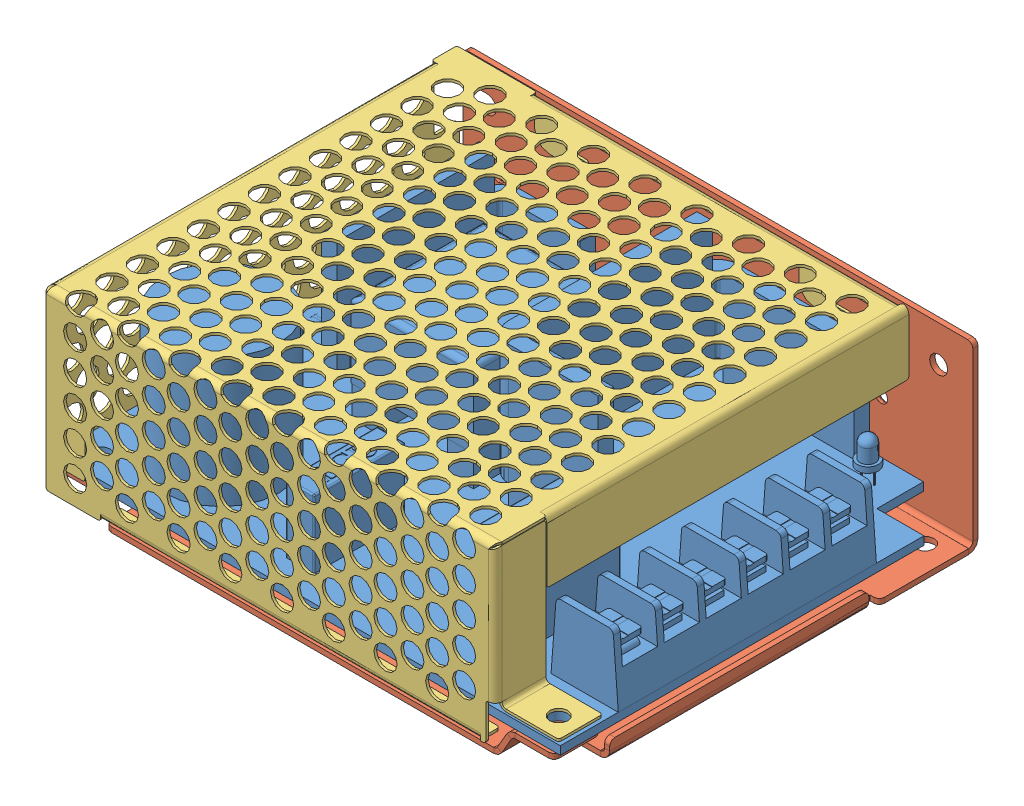
SolidWorks assembly Fuente de poder, configuration По умолчанию. Lengths in mm.
Overall size (99.45 35.23 81.3).
3 component instances, 3 part files, 6 mates.
Components (placement in the parent):
- БП MW RD-35-R8-1: БП MW RD-35-R8 [По умолчанию] at origin size (97.91 28.9 79.31)
- Основание БП-1: Основание БП [По умолчанию] at (0 -4.5229 -0.25) size (98.6 35.1 81)
- Крышка БП-1: Крышка БП [По умолчанию] at (-6.45 29.7 0.55) x (-1 0 0) z (0 0 -1) size (98.4 35 80)
Mates (geometry in assembly coordinates):
- Концентричный7: concentric anti-aligned: cylinder of БП MW RD-35-R8-1 through (-44.25 1.6 35.25) axis (0 -1 0) radius 1.75; circle of Основание БП-1
- Концентричный8: concentric anti-aligned: cylinder of БП MW RD-35-R8-1 through (44.25 1.6 35.25) axis (0 -1 0) radius 1.75; cylinder of Основание БП-1 through (44.25 0 35.25) axis (0 1 0) radius 1.25
- Совпадение7: coincident anti-aligned: plane of БП MW RD-35-R8-1 through (0 0 0) normal (0 -1 0); plane of Основание БП-1 through (-0.5774 0 -0.25) normal (0 1 0)
- Совпадение9: coincident anti-aligned: plane of БП MW RD-35-R8-1 through (0 1.6 0) normal (0 1 0); plane of Крышка БП-1 through (-6.45 1.6 0.55) normal (0 -1 0)
- Концентричный63: concentric anti-aligned: cylinder of БП MW RD-35-R8-1 through (44.25 1.6 35.25) axis (0 -1 0) radius 1.75; cylinder of Крышка БП-1 through (44.25 1.6 35.25) axis (0 1 0) radius 1.75
- Параллельность1: parallel aligned: plane of Основание БП-1 through (-49.3 -5.5229 40.25) normal (0 0 1); plane of Крышка БП-1 through (-6.45 29.7 40.55) normal (0 0 1)
